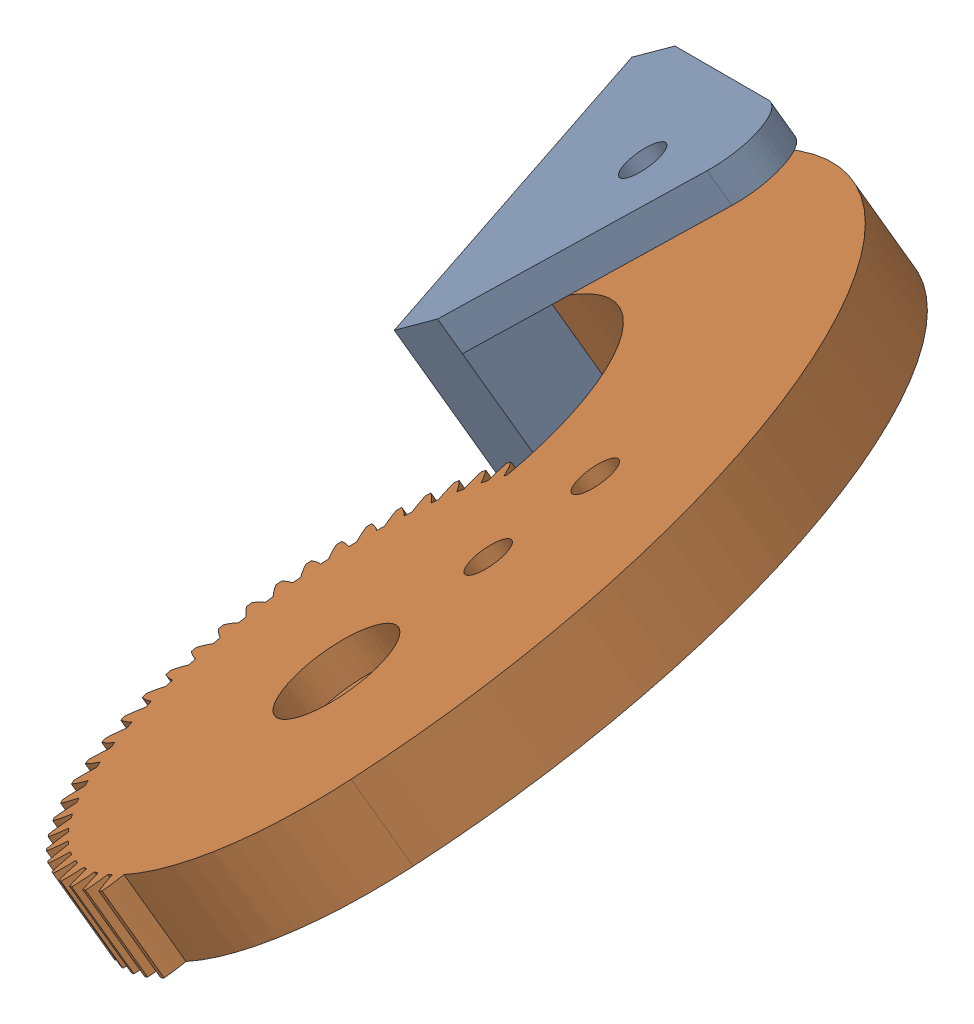
SolidWorks assembly Złożenie7, configuration Domyślna. Lengths in mm.
Overall size (44.29 32.31 61.31).
2 component instances, 2 part files, 3 mates.
Components (placement in the parent):
- Chwyt-1: Chwyt [Domyślna] at (93.516 -171.6593 20.5651) x (-0.818033 -0.567973 0.090709) z (0.533395 -0.808131 -0.249828) size (17.08 20 10)
- koło_zębate-1: koło_zębate [ISO - Spur gear 1M 30T 20PA 6FW ---S30A75H50L5.0N] at (114.1006 -171.5915 52.2868) x (0.533395 -0.808131 -0.249828) z (0.818033 0.567973 -0.090709) size (5 55.03 34.65)
Mates (geometry in assembly coordinates):
- Koncentryczne112: concentric aligned: cylinder of koło_zębate-1 through (105.1454 -173.0126 17.7501) axis (0.533395 -0.808131 -0.249828) radius 1.3; cylinder of Chwyt-1 through (106.2122 -174.6289 17.2504) axis (0.533395 -0.808131 -0.249828) radius 1.3
- Wspólnie87: coincident anti-aligned: plane of koło_zębate-1 through (116.7676 -175.6322 51.0377) normal (0.533395 -0.808131 -0.249828); plane of Chwyt-1 through (97.5565 -174.4774 6.2855) normal (-0.533395 0.808131 0.249828)
- Równolegle10: parallel anti-aligned: plane of koło_zębate-1 through (133.2645 -223.8015 8.4418) normal (-0.818033 -0.567973 0.090709); plane of Chwyt-1 through (95.9701 -169.9554 20.293) normal (0.818033 0.567973 -0.090709)
